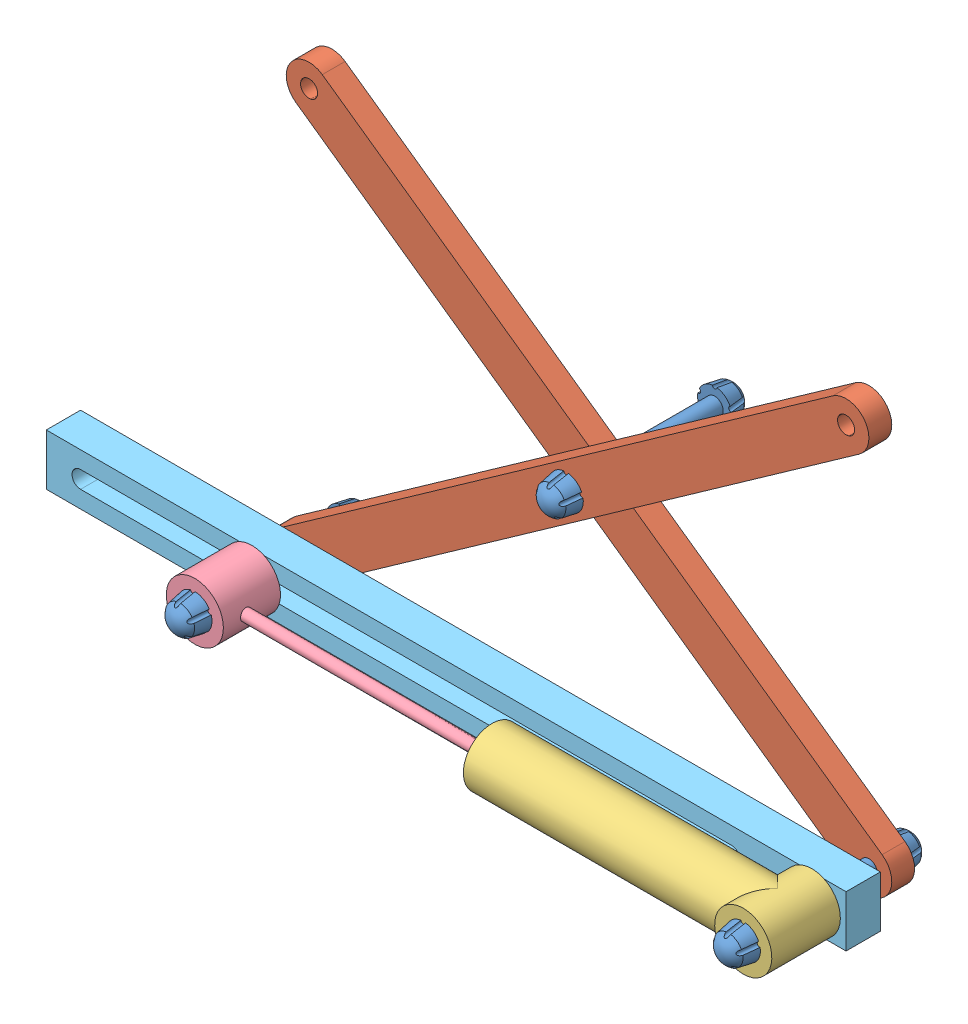
SolidWorks assembly Q10, configuration Default. Lengths in mm.
Overall size (700 402.02 260).
8 component instances, 5 part files, 20 mates.
Components (placement in the parent):
- Linkage_Bolt-1: Linkage_Bolt [Default] at (180 22.5 50) x (0.420895 -0.907109 0) z (0 0 1) size (30 29.87 170)
- Linkage_Coupling-1: Linkage_Coupling [Default] at (168.4578 352.4325 -50) x (0.816667 -0.57711 0) z (0 0 1) size (640 40 20)
- Linkage_Cylinder-1: Linkage_Cylinder [Default] at (670 22.5 30) x (0 1 0) z (0 0 1) size (50 275 60)
- Linkage_Piston-1: Linkage_Piston [Default] at (180 22.5 30) x (0 0 1) z (-1 0 0) size (50 50 325)
- Linkage_Coupling-2: Linkage_Coupling [Default] at (191.5422 6.1667 -30) x (0.816667 0.57711 0) z (0 0 1) size (640 40 20)
- Linkage_Bolt-2: Linkage_Bolt [Default] at (670 22.5 60) size (30 29.87 170)
- Linkage_Bolt-3: Linkage_Bolt [Default] at (425 195.6329 -30) size (30 29.87 170)
- Linkage_Base-2: Linkage_Base [Default] at origin size (700 45 30)
Mates (geometry in assembly coordinates):
- Coincident1: coincident aligned: plane of Linkage_Base-2 through (0 45 0) normal (0 0 1)
- Coincident2: coincident anti-aligned: plane of Linkage_Base-2 through (0 0 -30) normal (0 -1 0)
- Coincident3: coincident anti-aligned: plane of Linkage_Base-2 through (0 0 -30) normal (-1 0 0)
- Tangent1: tangent anti-aligned: cylinder of Linkage_Bolt-1 through (274 22.5 -80) axis (0 0 1) radius 7.5; plane of Linkage_Base-2 through (30 15 -30) normal (0 1 0)
- Tangent2: tangent anti-aligned: cylinder of Linkage_Bolt-2 through (670 22.5 -70) axis (0 0 1) radius 7.5; plane of Linkage_Base-2 through (30 15 -30) normal (0 1 0)
- Concentric1: concentric aligned: cylinder of Linkage_Bolt-1 through (274 22.5 -80) axis (0 0 1) radius 7.5; cylinder of Linkage_Piston-1 through (274 22.5 0) axis (0 0 1) radius 7.5
- Concentric2: concentric aligned: cylinder of Linkage_Cylinder-1 through (670 22.5 0) axis (0 0 1) radius 7.5; cylinder of Linkage_Bolt-2 through (670 22.5 -70) axis (0 0 1) radius 7.5
- Concentric3: concentric aligned: cylinder of Linkage_Coupling-2 through (472 247.8797 -50) axis (0 0 1) radius 7.5; cylinder of Linkage_Bolt-3 through (472 247.8797 -160) axis (0 0 1) radius 7.5
- Concentric4: concentric aligned: cylinder of Linkage_Coupling-1 through (472 247.8797 -70) axis (0 0 1) radius 7.5; cylinder of Linkage_Bolt-3 through (472 247.8797 -160) axis (0 0 1) radius 7.5
- Concentric5: concentric aligned: cylinder of Linkage_Bolt-1 through (274 22.5 -80) axis (0 0 1) radius 7.5; cylinder of Linkage_Coupling-2 through (274 22.5 -50) axis (0 0 1) radius 7.5
- Concentric6: concentric aligned: cylinder of Linkage_Coupling-1 through (670 22.5 -70) axis (0 0 1) radius 7.5; cylinder of Linkage_Bolt-2 through (670 22.5 -70) axis (0 0 1) radius 7.5
- Concentric8: concentric aligned: cylinder of Linkage_Cylinder-1 through (620 22.5 30) axis (-1 0 0) radius 15; cylinder of Linkage_Piston-1 through (574 22.5 30) axis (-1 0 0) radius 5
- Coincident4: coincident anti-aligned: plane of Linkage_Bolt-1 through (274 22.5 50) normal (0 0 -1); plane of Linkage_Piston-1 through (274 22.5 50) normal (0 0 1)
- Coincident5: coincident anti-aligned: plane of Linkage_Cylinder-1 through (670 22.5 60) normal (0 0 1); plane of Linkage_Bolt-2 through (670 22.5 60) normal (0 0 -1)
- Distance1: distance = 140 mm anti-aligned: plane of Linkage_Cylinder-1 through (620 22.5 30) normal (-1 0 0); plane of Linkage_Piston-1 through (480 22.5 30) normal (1 0 0)
- Coincident11: coincident anti-aligned: plane of Linkage_Coupling-2 through (274 22.5 -30) normal (0 0 1); plane of Linkage_Bolt-3 through (472 247.8797 -30) normal (0 0 -1)
- Coincident12: coincident anti-aligned: plane of Linkage_Coupling-2 through (274 22.5 -30) normal (0 0 1); plane of Linkage_Base-2 through (0 45 -30) normal (0 0 -1)
- Coincident13: coincident anti-aligned: plane of Linkage_Coupling-1 through (274 473.2594 -50) normal (0 0 1); plane of Linkage_Coupling-2 through (274 22.5 -50) normal (0 0 -1)
- Concentric9: concentric aligned: cylinder of Linkage_Bolt-2 through (670 22.5 -70) axis (0 0 1) radius 7.5; cylinder of Linkage_Base-2 through (670 22.5 -30) axis (0 0 1) radius 7.5
- Coincident14: coincident anti-aligned: plane of Linkage_Cylinder-1 through (670 22.5 0) normal (0 0 -1); plane of Linkage_Base-2 through (0 45 0) normal (0 0 1)
